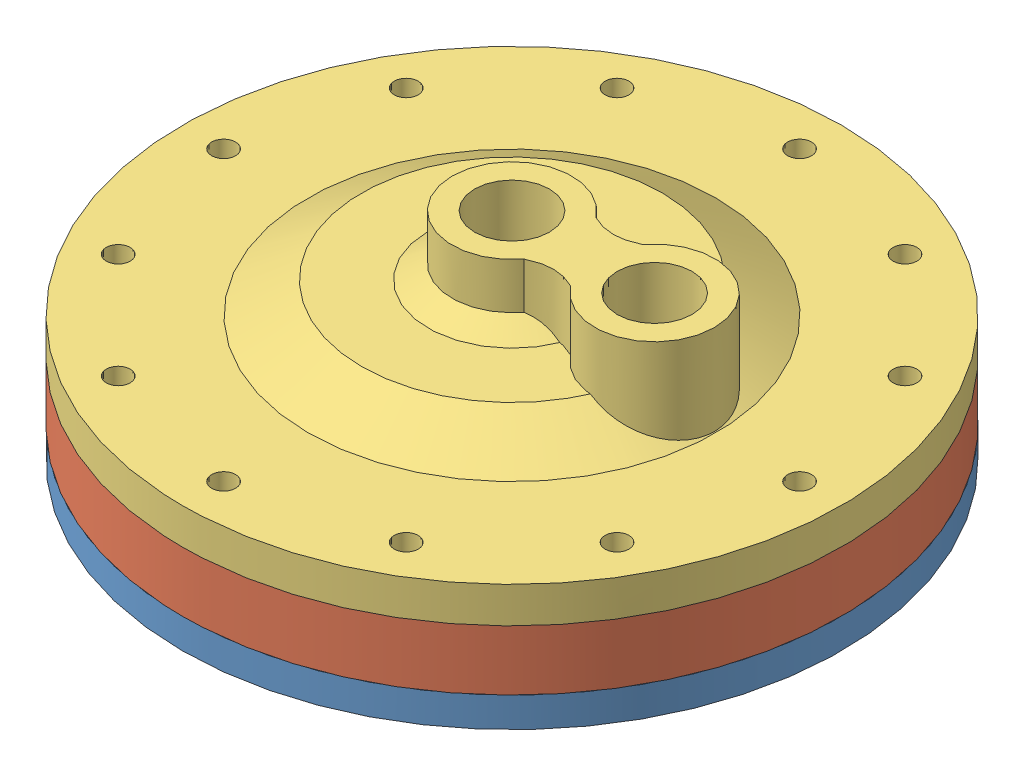
SolidWorks assembly Injector Assembly V4-2_bigger through holes, configuration Default. Lengths in mm.
Overall size (139.7 45.9 139.7).
3 component instances, 3 part files, 10 mates.
Components (placement in the parent):
- Injector V4-1: Injector V4 [Default] x (1 0 0) z (0 0 -1) size (139.7 15.63 139.7)
- Distribution Plate V4-1: Distribution Plate V4 [Default] at origin size (139.7 22.23 139.7)
- Top Plate V4-1: Top Plate V4 [Default] at (0 12.7 0) size (139.7 26.85 139.7)
Mates (geometry in assembly coordinates):
- Coincident1: coincident aligned: plane of Injector V4-1 through (0 0 0) normal (0 1 0)
- Coincident2: coincident anti-aligned: plane of Injector V4-1 through (0 0 0) normal (0 0 -1)
- Coincident3: coincident aligned: plane of Injector V4-1 through (0 0 0) normal (1 0 0)
- Coincident4: coincident anti-aligned: plane of Injector V4-1 through (0 -6.35 0) normal (0 -1 0); plane of FLANGE-1 through (0 -6.35 0) normal (0 1 0)
- Concentric1: concentric anti-aligned: cylinder of Injector V4-1 through (0 -6.35 0) axis (0 1 0) radius 69.85; cylinder of FLANGE-1 through (0 -26.67 0) axis (0 -1 0) radius 73.025
- Concentric2: concentric aligned: cylinder of Injector V4-1 through (30.48 -6.35 -52.7929) axis (0 1 0) radius 3.2639; cylinder of FLANGE-1 through (30.48 -25.4 -52.7929) axis (0 1 0) radius 2.4892
- Concentric3: concentric aligned: cylinder of FLANGE-1 through (0 -26.67 0) axis (0 -1 0) radius 73.025; cylinder of Distribution Plate V4-1 through (0 12.7 0) axis (0 -1 0) radius 69.85
- Coincident5: coincident anti-aligned: plane of Injector V4-1 through (0 0 0) normal (0 1 0); plane of Distribution Plate V4-1 through (0 0 0) normal (0 -1 0)
- Concentric4: concentric aligned: cylinder of Distribution Plate V4-1 through (0 12.7 0) axis (0 -1 0) radius 69.85; cylinder of Top Plate V4-1 through (0 20.32 0) axis (0 -1 0) radius 69.85
- Coincident6: coincident anti-aligned: plane of Distribution Plate V4-1 through (0 12.7 0) normal (0 1 0); plane of Top Plate V4-1 through (0 12.7 0) normal (0 -1 0)
